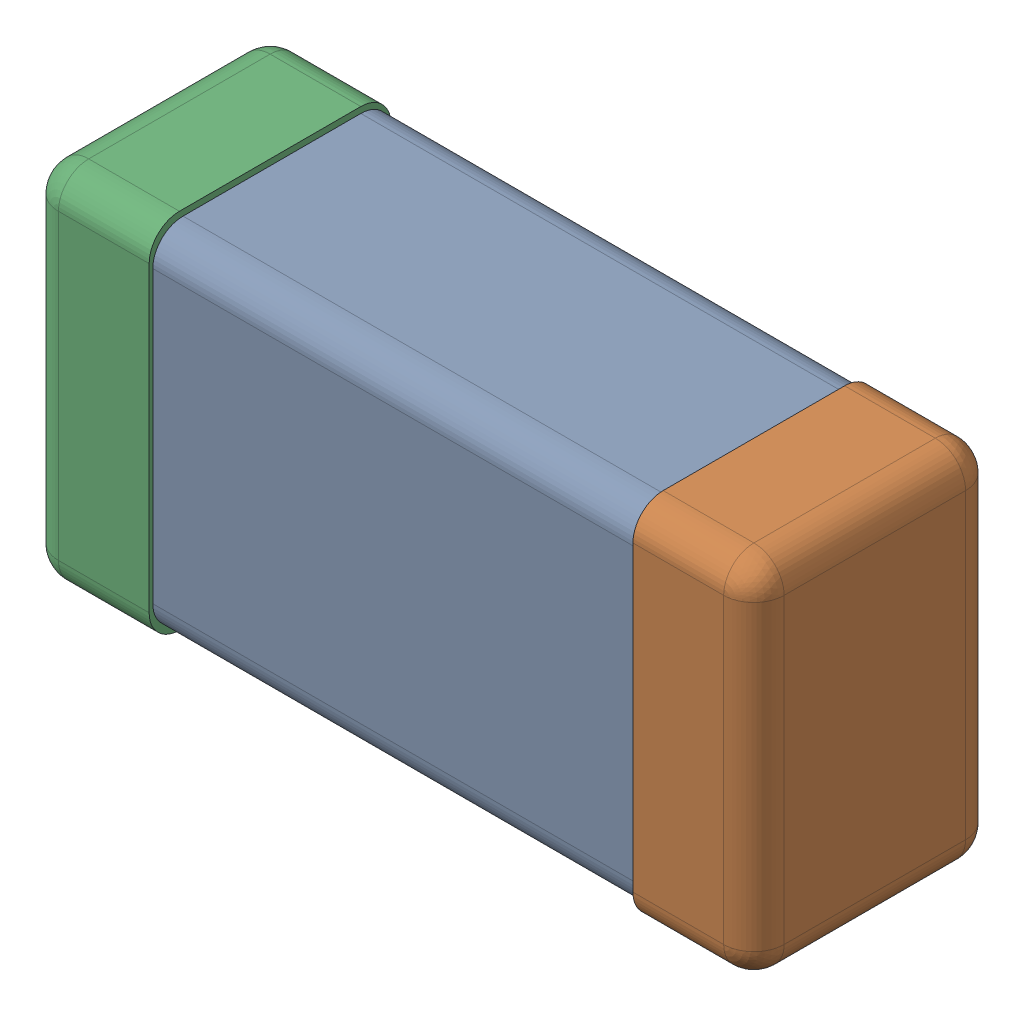
SolidWorks assembly C0201_020_22, configuration Standard. Lengths in mm.
Overall size (0.6 0.3 0.2).
4 component instances, 3 part files, 0 mates.
Components (placement in the parent):
- C0201_020_23-1: C0201_020_23 [Standard] at origin size (0.6 0.3 0.2)
  - Part 3_2-1: Part 3_2 [Standard] at (0 0 -7.3015) size (0.5 0.29 0.2)
  - Part 2_2-1: Part 2_2 [Standard] at (0 0 -7.3) size (0.1 0.3 0.2)
  - Part 1_2-1: Part 1_2 [Standard] at (0 0 -7.3) size (0.1 0.3 0.2)
